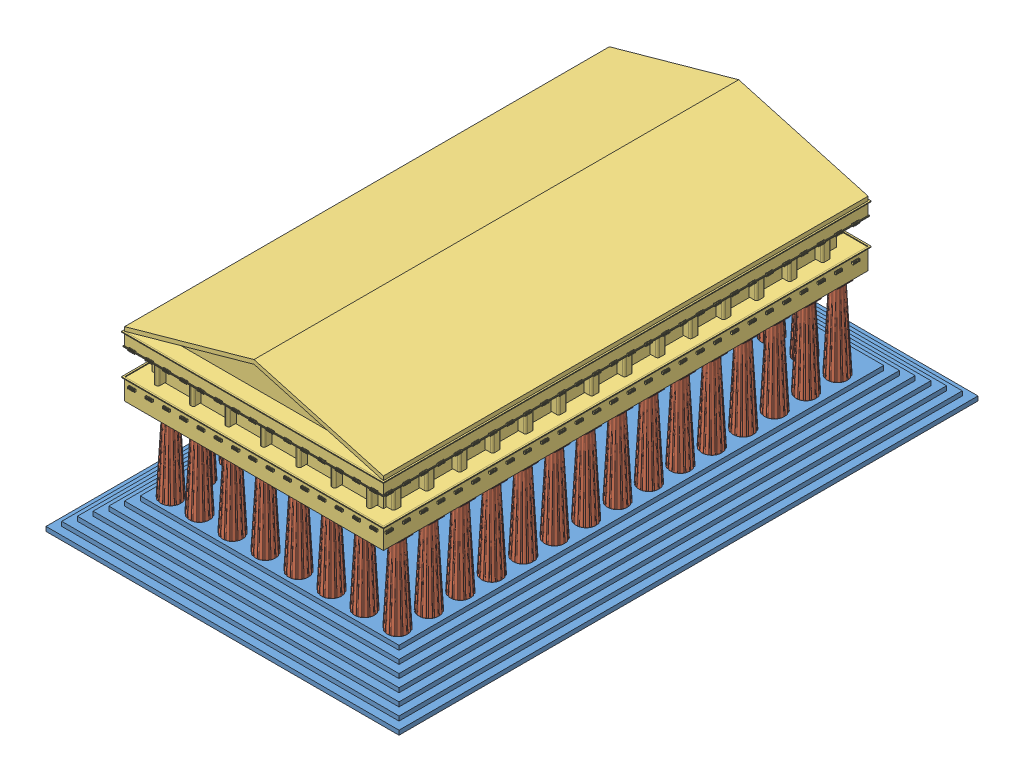
SolidWorks assembly assem_final2top, configuration Default. Lengths in mm.
Overall size (44.94 27.46 73.7).
45 component instances, 3 part files, 4 mates.
Components (placement in the parent):
- parthenon_base-1: parthenon_base [Default] at (-11.0896 3.1982 28.3251) size (44.94 3.92 73.7)
- parthenon_pillar-2: parthenon_pillar [Default] at (9.9021 3.2982 -4.2756) x (1 0 0) z (0 1 0) size (2.62 2.64 10.72)
- parthenon_pillar-3: parthenon_pillar [Default] at (9.9021 3.2982 -8.2756) x (1 0 0) z (0 1 0) size (2.62 2.64 10.72)
- parthenon_pillar-4: parthenon_pillar [Default] at (9.9021 3.2982 -12.2756) x (1 0 0) z (0 1 0) size (2.62 2.64 10.72)
- parthenon_pillar-5: parthenon_pillar [Default] at (9.9021 3.2982 -16.2756) x (1 0 0) z (0 1 0) size (2.62 2.64 10.72)
- parthenon_pillar-6: parthenon_pillar [Default] at (9.9021 3.2982 -20.2756) x (1 0 0) z (0 1 0) size (2.62 2.64 10.72)
- parthenon_pillar-7: parthenon_pillar [Default] at (9.9021 3.2982 -24.2756) x (1 0 0) z (0 1 0) size (2.62 2.64 10.72)
- parthenon_pillar-8: parthenon_pillar [Default] at (9.9021 3.2982 -28.2756) x (1 0 0) z (0 1 0) size (2.62 2.64 10.72)
- parthenon_pillar-9: parthenon_pillar [Default] at (9.9021 3.2982 -32.2756) x (1 0 0) z (0 1 0) size (2.62 2.64 10.72)
- parthenon_pillar-10: parthenon_pillar [Default] at (9.9021 3.2982 -36.2756) x (1 0 0) z (0 1 0) size (2.62 2.64 10.72)
- parthenon_pillar-11: parthenon_pillar [Default] at (9.9021 3.2982 -40.2756) x (1 0 0) z (0 1 0) size (2.62 2.64 10.72)
- parthenon_pillar-12: parthenon_pillar [Default] at (9.9021 3.2982 -44.2756) x (1 0 0) z (0 1 0) size (2.62 2.64 10.72)
- parthenon_pillar-13: parthenon_pillar [Default] at (9.9021 3.2982 -48.2756) x (1 0 0) z (0 1 0) size (2.62 2.64 10.72)
- parthenon_pillar-14: parthenon_pillar [Default] at (9.9021 3.2982 -52.2756) x (1 0 0) z (0 1 0) size (2.62 2.64 10.72)
- parthenon_pillar-15: parthenon_pillar [Default] at (9.9021 3.2982 -56.2756) x (1 0 0) z (0 1 0) size (2.62 2.64 10.72)
- parthenon_pillar-16: parthenon_pillar [Default] at (9.9021 3.2982 -60.2756) x (1 0 0) z (0 1 0) size (2.62 2.64 10.72)
- parthenon_pillar-17: parthenon_pillar [Default] at (-18.9519 3.2982 -4.2756) x (1 0 0) z (0 1 0) size (2.62 2.64 10.72)
- parthenon_pillar-18: parthenon_pillar [Default] at (-18.9519 3.2982 -8.2756) x (1 0 0) z (0 1 0) size (2.62 2.64 10.72)
- parthenon_pillar-19: parthenon_pillar [Default] at (-18.9519 3.2982 -12.2756) x (1 0 0) z (0 1 0) size (2.62 2.64 10.72)
- parthenon_pillar-20: parthenon_pillar [Default] at (-18.9519 3.2982 -16.2756) x (1 0 0) z (0 1 0) size (2.62 2.64 10.72)
- parthenon_pillar-21: parthenon_pillar [Default] at (-18.9519 3.2982 -20.2756) x (1 0 0) z (0 1 0) size (2.62 2.64 10.72)
- parthenon_pillar-22: parthenon_pillar [Default] at (-18.9519 3.2982 -24.2756) x (1 0 0) z (0 1 0) size (2.62 2.64 10.72)
- parthenon_pillar-23: parthenon_pillar [Default] at (-18.9519 3.2982 -28.2756) x (1 0 0) z (0 1 0) size (2.62 2.64 10.72)
- parthenon_pillar-24: parthenon_pillar [Default] at (-18.9519 3.2982 -32.2756) x (1 0 0) z (0 1 0) size (2.62 2.64 10.72)
- parthenon_pillar-25: parthenon_pillar [Default] at (-18.9519 3.2982 -36.2756) x (1 0 0) z (0 1 0) size (2.62 2.64 10.72)
- parthenon_pillar-26: parthenon_pillar [Default] at (-18.9519 3.2982 -40.2756) x (1 0 0) z (0 1 0) size (2.62 2.64 10.72)
- parthenon_pillar-27: parthenon_pillar [Default] at (-18.9519 3.2982 -44.2756) x (1 0 0) z (0 1 0) size (2.62 2.64 10.72)
- parthenon_pillar-28: parthenon_pillar [Default] at (-18.9519 3.2982 -48.2756) x (1 0 0) z (0 1 0) size (2.62 2.64 10.72)
- parthenon_pillar-29: parthenon_pillar [Default] at (-18.9519 3.2982 -52.2756) x (1 0 0) z (0 1 0) size (2.62 2.64 10.72)
- parthenon_pillar-30: parthenon_pillar [Default] at (-18.9519 3.2982 -56.2756) x (1 0 0) z (0 1 0) size (2.62 2.64 10.72)
- parthenon_pillar-31: parthenon_pillar [Default] at (-18.9519 3.2982 -60.2756) x (1 0 0) z (0 1 0) size (2.62 2.64 10.72)
- parthenon_pillar-32: parthenon_pillar [Default] at (5.7021 3.2982 -4.2756) x (1 0 0) z (0 1 0) size (2.62 2.64 10.72)
- parthenon_pillar-33: parthenon_pillar [Default] at (1.5021 3.2982 -4.2756) x (1 0 0) z (0 1 0) size (2.62 2.64 10.72)
- parthenon_pillar-34: parthenon_pillar [Default] at (-2.6979 3.2982 -4.2756) x (1 0 0) z (0 1 0) size (2.62 2.64 10.72)
- parthenon_pillar-35: parthenon_pillar [Default] at (-6.8979 3.2982 -4.2756) x (1 0 0) z (0 1 0) size (2.62 2.64 10.72)
- parthenon_pillar-36: parthenon_pillar [Default] at (-11.0979 3.2982 -4.2756) x (1 0 0) z (0 1 0) size (2.62 2.64 10.72)
- parthenon_pillar-37: parthenon_pillar [Default] at (-15.2979 3.2982 -4.2756) x (1 0 0) z (0 1 0) size (2.62 2.64 10.72)
- parthenon_pillar-38: parthenon_pillar [Default] at (9.9021 3.2982 -60.2756) x (1 0 0) z (0 1 0) size (2.62 2.64 10.72)
- parthenon_pillar-39: parthenon_pillar [Default] at (5.7021 3.2982 -60.2756) x (1 0 0) z (0 1 0) size (2.62 2.64 10.72)
- parthenon_pillar-40: parthenon_pillar [Default] at (1.5021 3.2982 -60.2756) x (1 0 0) z (0 1 0) size (2.62 2.64 10.72)
- parthenon_pillar-41: parthenon_pillar [Default] at (-2.6979 3.2982 -60.2756) x (1 0 0) z (0 1 0) size (2.62 2.64 10.72)
- parthenon_pillar-42: parthenon_pillar [Default] at (-6.8979 3.2982 -60.2756) x (1 0 0) z (0 1 0) size (2.62 2.64 10.72)
- parthenon_pillar-43: parthenon_pillar [Default] at (-11.0979 3.2982 -60.2756) x (1 0 0) z (0 1 0) size (2.62 2.64 10.72)
- parthenon_pillar-44: parthenon_pillar [Default] at (-15.2979 3.2982 -60.2756) x (1 0 0) z (0 1 0) size (2.62 2.64 10.72)
- pillar_above-1: pillar_above [Default] at (62.4863 13.9232 -9.1936) size (33.34 12.82 62.1)
Mates (geometry in assembly coordinates):
- Coincident2: coincident anti-aligned: plane of parthenon_base-1 through (-11.0896 3.1982 28.3251) normal (0 1 0); plane of parthenon_pillar-2 through (17.7554 3.1982 26.6148) normal (0 -1 0)
- Distance1: distance = 0 mm anti-aligned: plane of pillar_above-1 through (62.4863 13.9232 -9.1936) normal (0 -1 0); plane of parthenon_pillar-2 through (9.9021 13.9232 -4.2756) normal (0 1 0)
- Parallel1: parallel aligned: line of parthenon_pillar-2 through (16.768 13.9232 27.6023) axis (1 0 0); line of pillar_above-1 through (-13.9935 13.9232 29.1023) axis (1 0 0)
- Distance2: distance = 2 mm aligned: plane of pillar_above-1 through (18.9465 15.8232 29.6023) normal (0 0 1); plane of parthenon_pillar-35 through (-0.032 13.9232 27.6023) normal (0 0 1)
